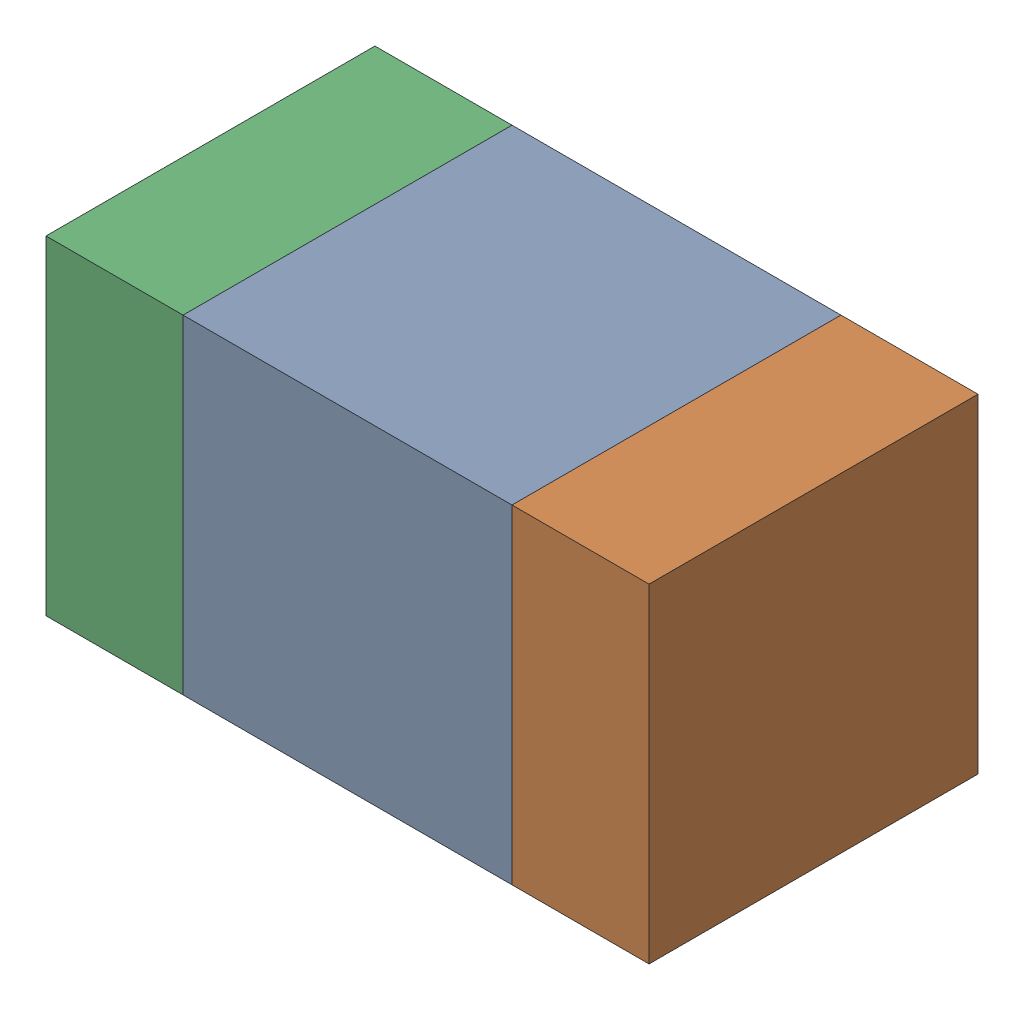
SolidWorks assembly C324_2PCB, configuration Default. Lengths in mm.
Overall size (1.1 0.6 0.6).
6 component instances, 2 part files, 0 mates.
Components (placement in the parent):
- 761606048-1: 761606048 [Default] at (136.5 86.4 -2.2638) size (0.6 0.6 0.6)
  - Extruded_9-1: Extruded_9 [Default] at origin size (0.6 0.6 0.6)
- 854785160-1: 854785160 [Default] at (136.925 86.4 -2.2638) size (0.25 0.6 0.6)
  - Extruded_19-1: Extruded_19 [Default] at origin size (0.25 0.6 0.6)
- 854785160-2: 854785160 [Default] at (136.075 86.4 -2.2638) size (0.25 0.6 0.6)
  - Extruded_19-1: Extruded_19 [Default] at origin size (0.25 0.6 0.6)
